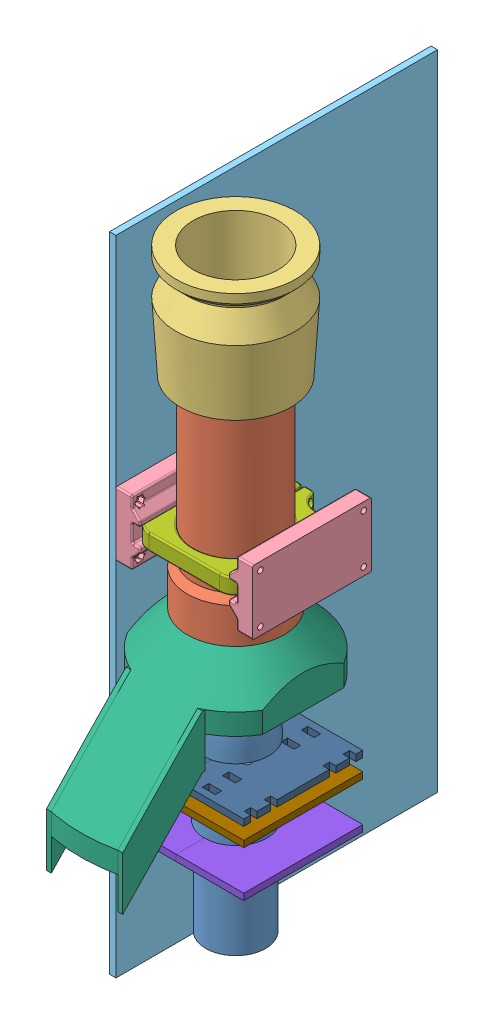
SolidWorks assembly full_assembly, configuration Default. Lengths in mm.
Overall size (95.51 400 264.23).
11 component instances, 10 part files, 43 mates.
Components (placement in the parent):
- drill-1: drill [Default] at (53.9901 98.18 150.1602) size (42 186 41.34)
- grinder-1: grinder [Default] at (53.9901 313.28 150.1602) x (-0.299531 0 -0.954087) z (-0.954087 0 0.299531) size (60 125 60)
- shaker-1: shaker [Default] at (53.9901 383.28 150.1602) x (-0.184647 0 -0.982805) z (-0.982805 0 0.184647) size (74 70 74)
- slide_interface-1: slide_interface [Default] at (11.4901 227.78 145.1602) x (0 0 -1) z (1 0 0) size (74 40 15)
- slide_interface-2: slide_interface [Default] at (96.4901 227.78 145.1602) x (0 0 1) z (-1 0 0) size (74 40 15)
- sides-1: sides [Default] at (11.4901 133.7912 82.1602) x (0 0 1) z (0 -1 0) size (200 4 400)
- funnel-1: funnel [Default] at (53.9901 196.28 150.1602) x (0 0 -1) z (-1 0 0) size (145.23 114.67 91.02)
- slide_carriage-2: slide_carriage [Default] at (792.4967 31798.1625 2242.3138) size (64 10 74)
- drill_interface_large-1: drill_interface_large [Default] at (53.9901 69.68 150.1602) size (84 4 74)
- drill_interface_medium-1: drill_interface_medium [Default] at (53.9901 98.18 150.1602) size (84 4 74)
- drill_interface_small-1: drill_interface_small [Default] at (53.9901 109.68 150.1602) size (84 4 74)
Mates (geometry in assembly coordinates):
- Concentric1: concentric anti-aligned: cylinder of grinder-1 through (53.9901 313.28 150.1602) axis (0 1 0) radius 26; cylinder of Part5-2 through (53.9901 233.28 150.1602) axis (0 -1 0) radius 26
- Concentric2: concentric anti-aligned: cylinder of grinder-1 through (53.9901 313.28 150.1602) axis (0 1 0) radius 26; cylinder of shaker-1 through (53.9901 383.28 150.1602) axis (0 -1 0) radius 26.5
- Concentric3: concentric aligned: cylinder of drill-1 through (53.9901 118.38 150.1602) axis (0 -1 0) radius 5; cylinder of grinder-1 through (53.9901 202.68 150.1602) axis (0 -1 0) radius 23
- Coincident1: coincident anti-aligned: plane of Part5-2 through (21.9901 233.28 -10.0893) normal (-1 0 0); plane of slide_interface-1 through (21.4901 227.78 145.1602) normal (1 0 0)
- Coincident2: coincident anti-aligned: plane of Part5-2 through (-17.3545 233.28 -10.0893) normal (0 1 0); plane of slide_interface-1 through (11.4901 233.28 98.7262) normal (0 -1 0)
- Coincident3: coincident anti-aligned: plane of Part5-2 through (85.9901 233.28 -10.0893) normal (1 0 0); plane of slide_interface-2 through (86.4901 227.78 145.1602) normal (-1 0 0)
- Coincident4: coincident anti-aligned: plane of Part5-2 through (-17.3545 233.28 -10.0893) normal (0 1 0); plane of slide_interface-2 through (96.4901 233.28 191.5942) normal (0 -1 0)
- Coincident5: coincident aligned: plane of slide_interface-1 through (21.4901 207.78 182.1602) normal (0 0 1); plane of slide_interface-2 through (86.4901 207.78 182.1602) normal (0 0 1)
- Parallel1: parallel aligned: plane of drill-1 through (32.9901 69.68 142.3602) normal (-1 0 0); plane of Part5-2 through (21.9901 233.28 -10.0893) normal (-1 0 0)
- Distance1: distance = 35 mm aligned: plane of Part5-2 through (-17.3545 223.28 -10.0893) normal (0 -1 0); plane of grinder-1 through (53.9901 188.28 150.1602) normal (0 -1 0)
- Coincident8: coincident anti-aligned: plane of slide_interface-1 through (11.4901 227.78 145.1602) normal (-1 0 0); plane of sides-1 through (11.4901 133.7912 82.1602) normal (1 0 0)
- Parallel2: parallel anti-aligned: plane of slide_interface-1 through (21.4901 247.78 182.1602) normal (0 1 0); plane of sides-1 through (7.4901 -16.72 -17.8398) normal (0 -1 0)
- Coincident10: coincident anti-aligned: plane of drill-1 through (53.9901 199.68 150.1602) normal (0 1 0); plane of grinder-1 through (53.9901 199.68 150.1602) normal (0 -1 0)
- Coincident11: coincident anti-aligned: plane of grinder-1 through (46.2023 313.28 125.354) normal (0 1 0); plane of shaker-1 through (53.9901 313.28 150.1602) normal (0 -1 0)
- Coincident12: coincident aligned: plane of slide_interface-1 through (21.4901 207.78 182.1602) normal (0 0 1); plane of sides-1 through (7.4901 -16.72 182.1602) normal (0 0 1)
- Coincident13: coincident aligned: plane of shaker-1 through (47.1581 383.28 113.7964) normal (0 1 0); plane of sides-1 through (7.4901 383.28 -17.8398) normal (0 1 0)
- Concentric4: concentric anti-aligned: cylinder of grinder-1 through (53.9901 313.28 150.1602) axis (0 1 0) radius 26; cylinder of slide_carriage-1 through (53.9901 233.28 150.1602) axis (0 -1 0) radius 26
- Coincident14: coincident anti-aligned: plane of slide_interface-1 through (11.4901 233.28 98.7262) normal (0 -1 0); plane of slide_carriage-1 through (738.5067 233.28 2092.1536) normal (0 1 0)
- Coincident15: coincident anti-aligned: plane of slide_interface-2 through (96.4901 233.28 191.5942) normal (0 -1 0); plane of slide_carriage-1 through (738.5067 233.28 2092.1536) normal (0 1 0)
- Distance2: distance = 35 mm aligned: plane of slide_carriage-1 through (738.5067 223.28 2092.1536) normal (0 -1 0); plane of grinder-1 through (53.9901 188.28 150.1602) normal (0 -1 0)
- Distance3: distance = 0.5 mm anti-aligned: plane of slide_interface-2 through (86.4901 227.78 145.1602) normal (-1 0 0); plane of slide_carriage-1 through (85.9901 233.28 2092.1536) normal (1 0 0)
- Parallel3: parallel aligned: plane of drill-1 through (74.9901 69.68 142.3602) normal (1 0 0); plane of sides-1 through (11.4901 133.7912 82.1602) normal (1 0 0)
- Distance4: distance = 0.5 mm anti-aligned: plane of slide_interface-1 through (21.4901 227.78 145.1602) normal (1 0 0); plane of slide_carriage-1 through (21.9901 233.28 2092.1536) normal (-1 0 0)
- Concentric5: concentric anti-aligned: cylinder of grinder-1 through (53.9901 202.68 150.1602) axis (0 -1 0) radius 23; cylinder of funnel-1 through (53.9901 188.28 150.1602) axis (0 1 0) radius 22.75
- Coincident16: coincident anti-aligned: plane of grinder-1 through (53.9901 188.28 150.1602) normal (0 -1 0); plane of funnel-1 through (53.9901 188.28 150.1602) normal (0 1 0)
- Parallel4: parallel anti-aligned: plane of sides-1 through (11.4901 133.7912 82.1602) normal (1 0 0); plane of funnel-1 through (30.2818 140.7711 219.5627) normal (-1 0 0)
- Coincident20: coincident aligned: plane of slide_interface-1 through (21.4901 207.78 182.1602) normal (0 0 1); plane of slide_carriage-1 through (738.5067 233.28 182.1602) normal (0 0 1)
- Concentric6: concentric anti-aligned: cylinder of grinder-1 through (53.9901 313.28 150.1602) axis (0 1 0) radius 26; cylinder of slide_carriage-2 through (53.9901 233.28 150.1602) axis (0 -1 0) radius 26
- Distance5: distance = 35 mm aligned: plane of slide_carriage-2 through (792.4967 223.28 2242.3138) normal (0 -1 0); plane of grinder-1 through (53.9901 188.28 150.1602) normal (0 -1 0)
- Distance6: distance = 0.5 mm anti-aligned: plane of slide_interface-2 through (86.4901 227.78 145.1602) normal (-1 0 0); plane of slide_carriage-2 through (85.9901 233.28 2242.3138) normal (1 0 0)
- Distance7: distance = 0.5 mm anti-aligned: plane of slide_interface-1 through (21.4901 227.78 145.1602) normal (1 0 0); plane of slide_carriage-2 through (21.9901 233.28 2242.3138) normal (-1 0 0)
- Coincident24: coincident anti-aligned: plane of slide_interface-2 through (96.4901 233.28 191.5942) normal (0 -1 0); plane of slide_carriage-2 through (792.4967 233.28 2242.3138) normal (0 1 0)
- Coincident27: coincident anti-aligned: plane of slide_interface-1 through (11.4901 233.28 98.7262) normal (0 -1 0); plane of slide_carriage-2 through (792.4967 233.28 2242.3138) normal (0 1 0)
- Coincident28: coincident aligned: plane of slide_interface-1 through (21.4901 207.78 182.1602) normal (0 0 1); plane of slide_carriage-2 through (792.4967 233.28 182.1602) normal (0 0 1)
- Concentric7: concentric aligned: cylinder of drill-1 through (53.9901 113.68 150.1602) axis (0 -1 0) radius 12; cylinder of drill_interface_small-1 through (53.9901 113.68 150.1602) axis (0 -1 0) radius 12
- Coincident29: coincident aligned: plane of drill-1 through (53.9901 113.68 150.1602) normal (0 1 0); plane of drill_interface_small-1 through (53.9901 113.68 150.1602) normal (0 1 0)
- Concentric8: concentric aligned: cylinder of drill-1 through (53.9901 100.88 150.1602) axis (0 -1 0) radius 14; cylinder of drill_interface_medium-1 through (53.9901 102.18 150.1602) axis (0 -1 0) radius 14
- Coincident30: coincident anti-aligned: plane of drill-1 through (53.9901 98.18 150.1602) normal (0 1 0); plane of drill_interface_medium-1 through (53.9901 98.18 150.1602) normal (0 -1 0)
- Coincident31: coincident aligned: cylinder of drill-1 through (53.9901 63.68 150.1602) axis (0 1 0) radius 19.5; circle of drill_interface_large-1
- Coincident32: coincident anti-aligned: plane of drill-1 through (53.9901 69.68 150.1602) normal (0 1 0); plane of drill_interface_large-1 through (53.9901 69.68 150.1602) normal (0 -1 0)
- Parallel8: parallel anti-aligned: plane of sides-1 through (11.4901 133.7912 82.1602) normal (1 0 0); plane of drill_interface_medium-1 through (11.9901 102.18 150.1602) normal (-1 0 0)
- Parallel9: parallel anti-aligned: plane of sides-1 through (11.4901 133.7912 82.1602) normal (1 0 0); plane of drill_interface_small-1 through (11.9901 113.68 150.1602) normal (-1 0 0)
- Parallel10: parallel anti-aligned: plane of sides-1 through (11.4901 133.7912 82.1602) normal (1 0 0); plane of drill_interface_large-1 through (11.9901 73.68 150.1602) normal (-1 0 0)
